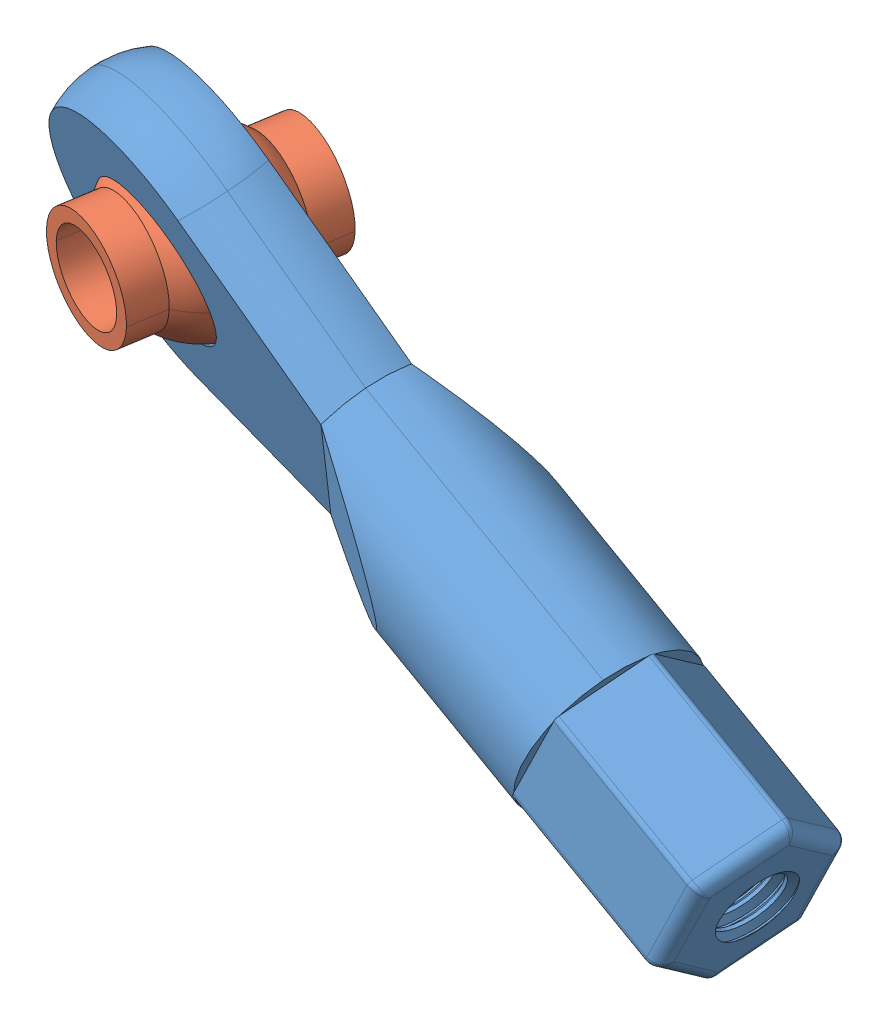
SolidWorks assembly M3_ball joint, configuration Default. Lengths in mm.
Overall size (33.25 24.16 14.74).
2 component instances, 2 part files, 2 mates.
Components (placement in the parent):
- Rótula M3 parte 2-1: Rótula M3 parte 2 [Predeterminado] at (40.7115 26.0165 38.073) x (0.224534 0.31636 -0.921684) z (0.307085 0.874671 0.375033) size (7.79 30.01 12.21)
- Rótula M3 parte 1-2: Rótula M3 parte 1 [Predeterminado] at (17.7293 35.1408 35.6173) x (-0.956256 0.178667 -0.23163) z (0.153318 0.980453 0.123314) size (6 7 6)
Mates (geometry in assembly coordinates):
- Concentric1: concentric: sphere of Rótula M3 parte 2-1; sphere of Rótula M3 parte 1-2
- Tangent1: tangent aligned: sphere of Rótula M3 parte 2-1; sphere of Rótula M3 parte 1-2
